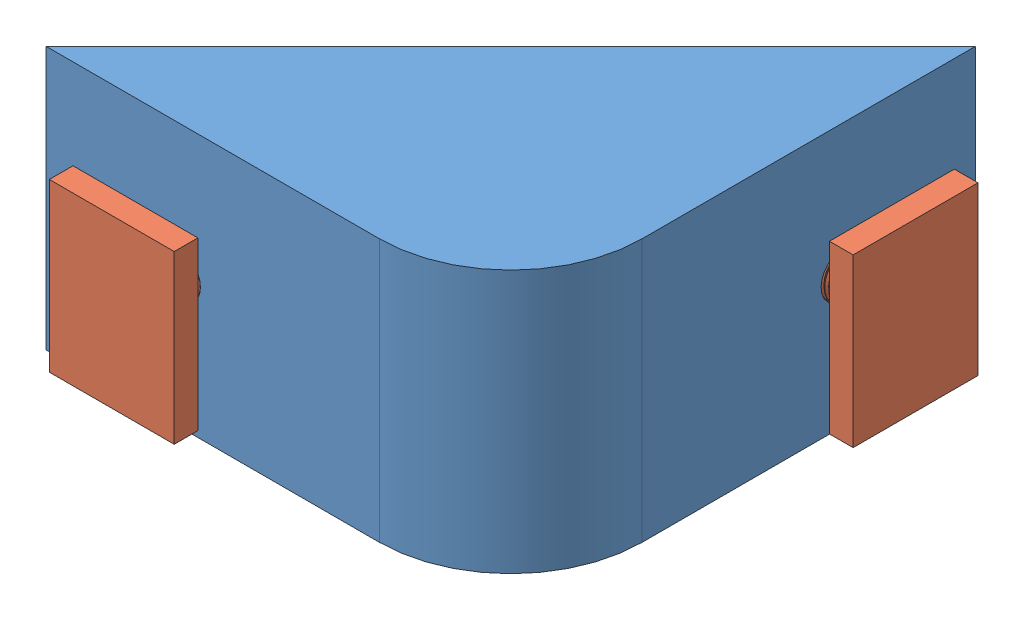
SolidWorks assembly Connector and Nut, configuration Default. Lengths in mm.
Overall size (40.79 20 40.35).
5 component instances, 3 part files, 9 mates.
Components (placement in the parent):
- connector-1: connector [Default] at (36.2342 15.8717 43.7398) size (35.36 20 35.36)
- T-bolt-1: T-bolt [Default] at (40.7722 15.8717 18.3844) x (-1 0 0) z (0 0 -1) size (17.8 12.7 9.5)
- hexagon nut style 1_is-2: hexagon nut style 1_is [IS 1364-3 - M3-W-N] at (28.8342 15.8717 18.3844) x (0 0.996107 0.088148) z (-1 0 0) size (5.5 6.35 2.4)
- T-bolt-2: T-bolt [Default] at (10.8788 15.8717 47.8359) x (0 0 -1) z (1 0 0) size (17.8 12.7 9.5)
- hexagon nut style 1_is-3: hexagon nut style 1_is [IS 1364-3 - M3-W-N] at (10.8788 15.8717 36.3398) x (0.175203 0.984532 0) z (0 0 -1) size (5.5 6.35 2.4)
Mates (geometry in assembly coordinates):
- Concentric1: concentric: circle of connector-1; circle of T-bolt-1
- Concentric2: concentric: cylinder of T-bolt-1 through (23.8722 15.8717 18.3844) axis (1 0 0) radius 1.5; cylinder of hexagon nut style 1_is-2 through (53.8717 15.8717 18.3844) axis (-1 0 0) radius 1.5
- Concentric3: concentric: circle of T-bolt-1; circle of hexagon nut style 1_is-2
- Coincident5: coincident: plane of connector-1 through (31.2342 15.8717 43.7398) normal (-1 0 0); plane of hexagon nut style 1_is-2 through (31.2342 10.3931 17.8996) normal (1 0 0)
- Concentric4: concentric: circle of connector-1; circle of T-bolt-2
- Parallel3: parallel: plane of connector-1 through (36.2342 25.8717 43.7398) normal (0 1 0); plane of T-bolt-2 through (15.6288 22.2217 46.9359) normal (0 1 0)
- Concentric51: concentric: cylinder of T-bolt-2 through (10.8788 15.8717 30.9359) axis (0 0 1) radius 1.5; cylinder of hexagon nut style 1_is-3 through (10.8788 15.8717 61.3773) axis (0 0 -1) radius 1.5
- Coincident8: coincident: plane of connector-1 through (36.2342 15.8717 38.7398) normal (0 0 -1); plane of hexagon nut style 1_is-3 through (9.9152 10.4568 38.7398) normal (0 0 1)
- Parallel4: parallel: plane of connector-1 through (36.2342 25.8717 43.7398) normal (0 1 0); plane of T-bolt-1 through (39.8722 9.5217 13.6344) normal (0 -1 0)
